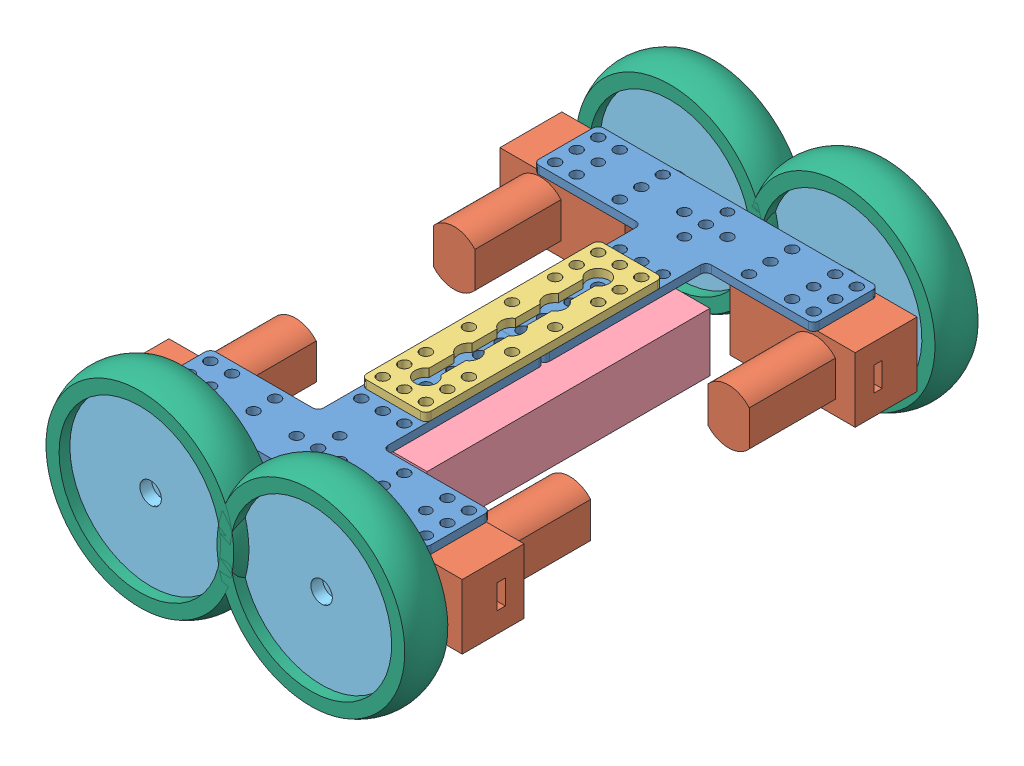
SolidWorks assembly robot_asm_idea, configuration Default. Lengths in mm.
Overall size (161.47 101.09 212.9).
16 component instances, 6 part files, 39 mates.
Components (placement in the parent):
- T-bracket-1: T-bracket [Default] at origin size (104 3 84)
- encoder_motor-1: encoder_motor [Default] at (65.95 -12 -24.45) x (0 0 1) z (0 -1 0) size (64 46.4 24)
- encoder_motor-2: encoder_motor [Default] at (-65.95 -12 -24.45) x (0 0 1) z (0 1 0) size (64 46.4 24)
- T-bracket-2: T-bracket [Default] at (0 0 120) x (-1 0 0) z (0 0 -1) size (104 3 84)
- bracket-1: bracket [Default] at (-12 3 104) size (24 3 88)
- encoder_motor-5: encoder_motor [Default] at (-65.95 -12 144.45) x (0 0 -1) z (0 -1 0) size (64 46.4 24)
- encoder_motor-9: encoder_motor [Default] at (65.95 -12 144.45) x (0 0 -1) z (0 1 0) size (64 46.4 24)
- battery-1: battery [Default] at (-12.5831 -24 113.9463) size (35 21.7 105)
- wheels-1: wheels [Default] at (31.75 -12 154.45) size (65.99 65.99 16)
- wheels-2: wheels [Default] at (-31.75 -12 154.45) size (65.99 65.99 16)
- wheels-4: wheels [Default] at (31.75 -12 -34.45) x (-1 0 0) z (0 0 -1) size (65.99 65.99 16)
- wheels-6: wheels [Default] at (-31.75 -12 -34.45) x (-1 0 0) z (0 0 -1) size (65.99 65.99 16)
- tire-1: tire [Default] at (-31.75 -12 158.45) x (0 0 1) z (-1 0 0) size (16 74 74)
- tire-2: tire [Default] at (31.75 -12 158.45) x (0 0 1) z (-0.987351 -0.158553 0) size (16 74 74)
- tire-4: tire [Default] at (31.75 -12 -38.45) x (0 0 -1) z (0.34202 -0.939693 0) size (16 74 74)
- tire-6: tire [Default] at (-31.75 -12 -38.45) x (0 0 -1) z (0.5 -0.866025 0) size (16 74 74)
Mates (geometry in assembly coordinates):
- Coincident1: coincident anti-aligned: plane of T-bracket-1 through (0 0 0) normal (0 -1 0); plane of encoder_motor-1 through (65.95 0 -24.45) normal (0 1 0)
- Coincident2: coincident anti-aligned: plane of T-bracket-1 through (0 0 0) normal (0 -1 0); plane of encoder_motor-2 through (-65.95 0 -24.45) normal (0 1 0)
- Concentric1: concentric aligned: cylinder of T-bracket-1 through (24 0 -20) axis (0 1 0) radius 2.05; cylinder of encoder_motor-1 through (24 -5.5 -20) axis (0 1 0) radius 1.95
- Concentric2: concentric aligned: cylinder of T-bracket-1 through (40 0 -20) axis (0 1 0) radius 2.05; cylinder of encoder_motor-1 through (40 -5.5 -20) axis (0 1 0) radius 1.95
- Concentric3: concentric aligned: cylinder of T-bracket-1 through (-40 0 -20) axis (0 1 0) radius 2.05; cylinder of encoder_motor-2 through (-40 -5.5 -20) axis (0 1 0) radius 1.95
- Concentric4: concentric aligned: cylinder of T-bracket-1 through (-24 0 -20) axis (0 1 0) radius 2.05; cylinder of encoder_motor-2 through (-24 -5.5 -20) axis (0 1 0) radius 1.95
- Coincident3: coincident anti-aligned: plane of T-bracket-1 through (0 3 0) normal (0 1 0); plane of bracket-1 through (-12 3 104) normal (0 -1 0)
- Coincident4: coincident anti-aligned: plane of T-bracket-2 through (0 3 120) normal (0 1 0); plane of bracket-1 through (-12 3 104) normal (0 -1 0)
- Concentric5: concentric aligned: cylinder of T-bracket-2 through (-8 0 92) axis (0 1 0) radius 2.05; cylinder of bracket-1 through (-8 3 92) axis (0 1 0) radius 2.05
- Concentric6: concentric aligned: cylinder of T-bracket-2 through (8 0 92) axis (0 1 0) radius 2.05; cylinder of bracket-1 through (8 3 92) axis (0 1 0) radius 2.05
- Concentric7: concentric aligned: cylinder of T-bracket-1 through (-8 0 28) axis (0 1 0) radius 2.05; cylinder of bracket-1 through (-8 3 28) axis (0 1 0) radius 2.05
- Concentric8: concentric aligned: cylinder of T-bracket-1 through (8 0 28) axis (0 1 0) radius 2.05; cylinder of bracket-1 through (8 3 28) axis (0 1 0) radius 2.05
- Coincident7: coincident anti-aligned: plane of T-bracket-2 through (0 0 120) normal (0 -1 0); plane of encoder_motor-5 through (-65.95 0 144.45) normal (0 1 0)
- Concentric11: concentric aligned: cylinder of T-bracket-2 through (-24 0 140) axis (0 1 0) radius 2.05; cylinder of encoder_motor-5 through (-24 -5.5 140) axis (0 1 0) radius 1.95
- Concentric12: concentric aligned: cylinder of T-bracket-2 through (-40 0 140) axis (0 1 0) radius 2.05; cylinder of encoder_motor-5 through (-40 -5.5 140) axis (0 1 0) radius 1.95
- Coincident10: coincident anti-aligned: plane of T-bracket-2 through (0 0 120) normal (0 -1 0); plane of encoder_motor-9 through (65.95 0 144.45) normal (0 1 0)
- Concentric16: concentric aligned: cylinder of T-bracket-2 through (40 0 140) axis (0 1 0) radius 2.05; cylinder of encoder_motor-9 through (40 -5.5 140) axis (0 1 0) radius 1.95
- Concentric17: concentric aligned: cylinder of T-bracket-2 through (24 0 140) axis (0 1 0) radius 2.05; cylinder of encoder_motor-9 through (24 -5.5 140) axis (0 1 0) radius 1.95
- Coincident11: coincident aligned: plane of encoder_motor-5 through (-65.95 -24 144.45) normal (0 -1 0); plane of battery-1 through (-12.5831 -24 113.9463) normal (0 -1 0)
- Parallel3: parallel anti-aligned: plane of encoder_motor-9 through (19.55 -10.25 153.45) normal (0 1 0); plane of wheels-1 through (29.7153 -10.15 160.5787) normal (0 -1 0)
- Concentric21: concentric aligned: cylinder of encoder_motor-9 through (31.75 -12 153.45) axis (0 0 -1) radius 2.7; cylinder of wheels-1 through (31.75 -12 160.5787) axis (0 0 -1) radius 2.75
- Coincident13: coincident anti-aligned: plane of encoder_motor-9 through (19.55 -10.25 146.45) normal (0 0 1); plane of wheels-1 through (31.75 -12 146.45) normal (0 0 -1)
- Parallel4: parallel anti-aligned: plane of encoder_motor-5 through (-19.55 -10.25 153.45) normal (0 1 0); plane of wheels-2 through (-33.7847 -10.15 160.5787) normal (0 -1 0)
- Concentric22: concentric aligned: cylinder of encoder_motor-5 through (-31.75 -12 153.45) axis (0 0 -1) radius 2.7; cylinder of wheels-2 through (-31.75 -12 160.5787) axis (0 0 -1) radius 2.75
- Coincident14: coincident anti-aligned: plane of encoder_motor-5 through (-19.55 -10.25 146.45) normal (0 0 1); plane of wheels-2 through (-31.75 -12 146.45) normal (0 0 -1)
- Parallel5: parallel anti-aligned: plane of encoder_motor-1 through (19.55 -10.25 -33.45) normal (0 1 0); plane of wheels-4 through (33.7847 -10.15 -40.5787) normal (0 -1 0)
- Concentric23: concentric aligned: cylinder of encoder_motor-1 through (31.75 -12 -33.45) axis (0 0 1) radius 2.7; cylinder of wheels-4 through (31.75 -12 -40.5787) axis (0 0 1) radius 2.75
- Coincident15: coincident anti-aligned: plane of encoder_motor-1 through (19.55 -10.25 -26.45) normal (0 0 -1); plane of wheels-4 through (31.75 -12 -26.45) normal (0 0 1)
- Parallel6: parallel anti-aligned: plane of encoder_motor-2 through (-19.55 -10.25 -33.45) normal (0 1 0); plane of wheels-6 through (-29.7153 -10.15 -40.5787) normal (0 -1 0)
- Concentric24: concentric aligned: cylinder of encoder_motor-2 through (-31.75 -12 -33.45) axis (0 0 1) radius 2.7; cylinder of wheels-6 through (-31.75 -12 -40.5787) axis (0 0 1) radius 2.75
- Coincident16: coincident anti-aligned: plane of encoder_motor-2 through (-19.55 -10.25 -26.45) normal (0 0 -1); plane of wheels-6 through (-31.75 -12 -26.45) normal (0 0 1)
- Concentric25: concentric aligned: cylinder of wheels-2 through (-31.75 -12 162.45) axis (0 0 -1) radius 33; cylinder of tire-1 through (-31.75 -12 -532.0168) axis (0 0 -1) radius 33
- Coincident17: coincident anti-aligned: plane of wheels-2 through (-31.75 -12 162.45) normal (0 0 1); plane of tire-1 through (-31.75 21 162.45) normal (0 0 -1)
- Concentric26: concentric aligned: cylinder of wheels-1 through (31.75 -12 162.45) axis (0 0 -1) radius 33; cylinder of tire-2 through (31.75 -12 -532.0168) axis (0 0 -1) radius 33
- Coincident18: coincident anti-aligned: plane of wheels-1 through (31.75 -12 162.45) normal (0 0 1); plane of tire-2 through (26.5178 20.5826 162.45) normal (0 0 -1)
- Concentric27: concentric aligned: cylinder of wheels-4 through (31.75 -12 -42.45) axis (0 0 1) radius 33; cylinder of tire-4 through (31.75 -12 652.0168) axis (0 0 1) radius 33
- Coincident19: coincident anti-aligned: plane of wheels-4 through (31.75 -12 -42.45) normal (0 0 -1); plane of tire-4 through (62.7599 -0.7133 -42.45) normal (0 0 1)
- Concentric28: concentric aligned: cylinder of wheels-6 through (-31.75 -12 -42.45) axis (0 0 1) radius 33; cylinder of tire-6 through (-31.75 -12 652.0168) axis (0 0 1) radius 33
- Coincident20: coincident anti-aligned: plane of wheels-6 through (-31.75 -12 -42.45) normal (0 0 -1); plane of tire-6 through (-3.1712 4.5 -42.45) normal (0 0 1)
